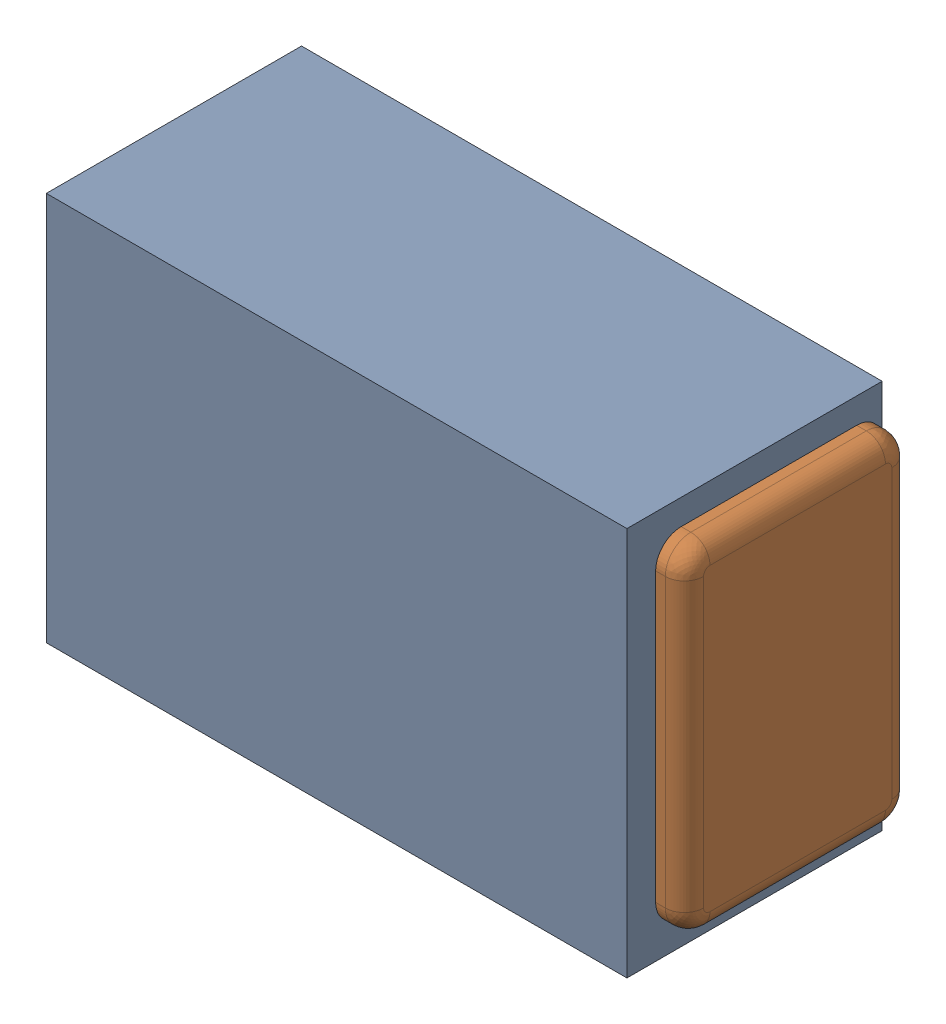
SolidWorks assembly C16, configuration Default. Lengths in mm.
Overall size (1 0.61 0.4).
3 component instances, 2 part files, 0 mates.
Components (placement in the parent):
- 1088880352-1: 1088880352 [Default] at (12.25 20.475 0) size (0.91 0.61 0.4)
  - Extruded-28-1: Extruded-28 [Default] at origin size (0.91 0.61 0.4)
- C0402-1: C0402 [Default] at (12.2501 20.4751 0) x (1 0 0) z (0 -1 0) size (1 0.36 0.54)
